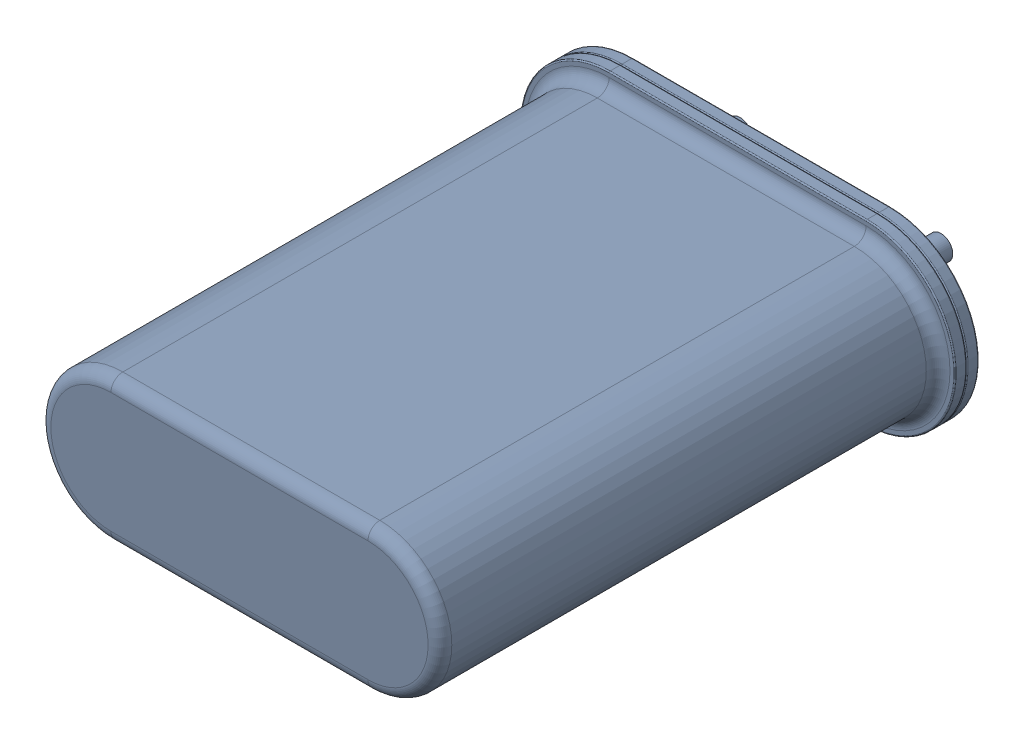
SolidWorks assembly X1, configuration Default. Lengths in mm.
Overall size (11 4.5 15.2).
2 component instances, 1 part files, 0 mates.
Components (placement in the parent):
- Open CASCADE STEP translator 6.8 1.2.1-1: Open CASCADE STEP translator 6.8 1.2.1 [Default] at origin size (11 4.5 15.2)
  - Body_1_2-1: Body_1_2 [Default] at (2.5 0 0) x (1 0 0) z (0 -1 0) size (11 15.2 4.5)
